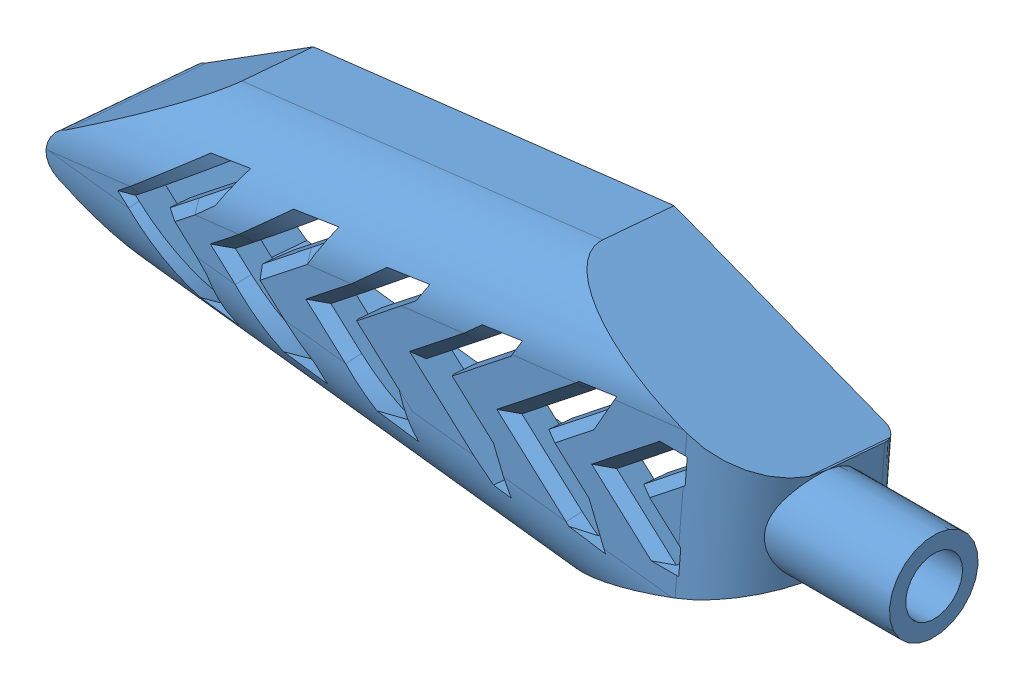
SolidWorks assembly ind right, configuration Default. Lengths in mm.
Overall size (170.98 54.51 34.63).
2 component instances, 2 part files, 1 mates.
Components (placement in the parent):
- ind thread-1: ind thread [Default] at (-15.6966 12.6871 30.1294) (suppressed, hidden)
- indnew-1: indnew [Default] at (-107.7473 13.9711 45.1473) x (1 0 0) z (0 -0.085189 -0.996365) size (170.98 52.12 30.3)
Mates (geometry in assembly coordinates):
- Concentric1: concentric anti-aligned: cylinder of ind thread-1 through (4.3034 12.6871 30.1294) axis (-1 0 0) radius 10; circle of indnew-1
